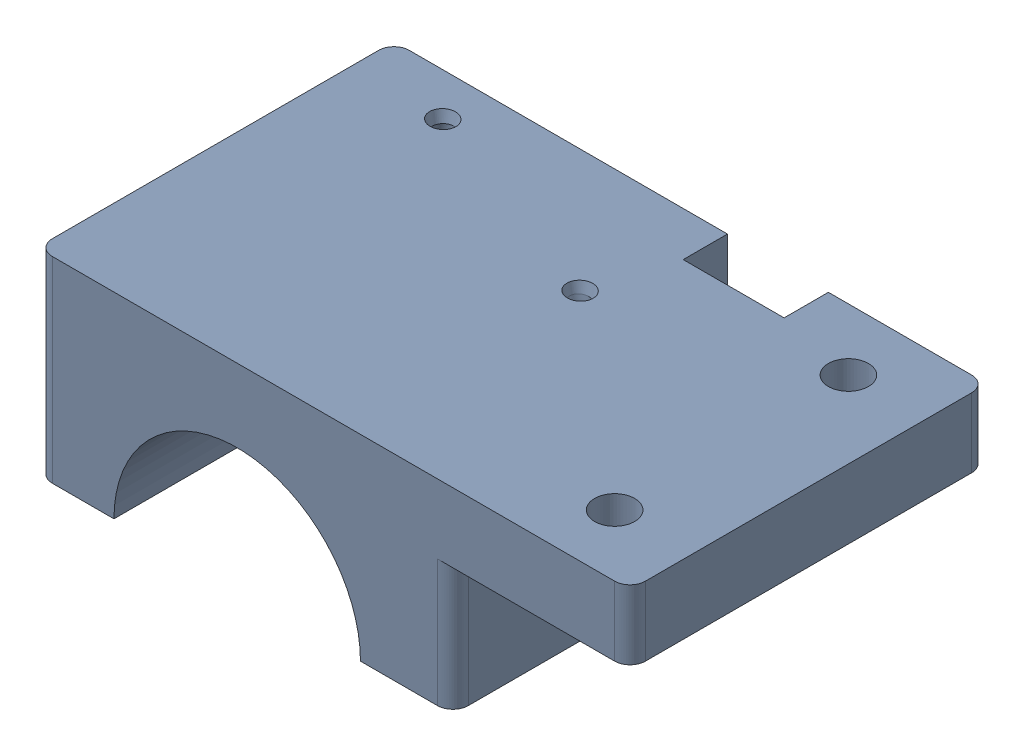
SolidWorks assembly lock_actuator_plates_with_inserts, configuration Default. Lengths in mm.
Overall size (77 25.54 46.35).
5 component instances, 2 part files, 0 mates.
Components (placement in the parent):
- top_lock_actuator_plate_Lock Actuator Base Plate-1: top_lock_actuator_plate_Lock Actuator Base Plate [Default] at (-75 -8 -58.3352) x (0 0 1) z (-1 0 0) size (46.35 25.5 77)
- m3_heat_set_insert_94180A331_94180A331-1: m3_heat_set_insert_94180A331_94180A331 [Default] at (-70 -24.5 -23.9352) x (-0.819465 0 -0.573129) z (-0.573129 0 0.819465) size (5.56 3.88 5.56)
- m3_heat_set_insert_94180A331_94180A331-2: m3_heat_set_insert_94180A331_94180A331 [Default] at (-28 -24.5 -9.7352) x (-0.819465 0 -0.573129) z (-0.573129 0 0.819465) size (5.56 3.88 5.56)
- m3_heat_set_insert_94180A331_94180A331-3: m3_heat_set_insert_94180A331_94180A331 [Default] at (-70 -24.5 -9.7352) x (-0.819465 0 -0.573129) z (-0.573129 0 0.819465) size (5.56 3.88 5.56)
- m3_heat_set_insert_94180A331_94180A331-4: m3_heat_set_insert_94180A331_94180A331 [Default] at (-28 -24.5 -23.9352) x (-0.819465 0 -0.573129) z (-0.573129 0 0.819465) size (5.56 3.88 5.56)
